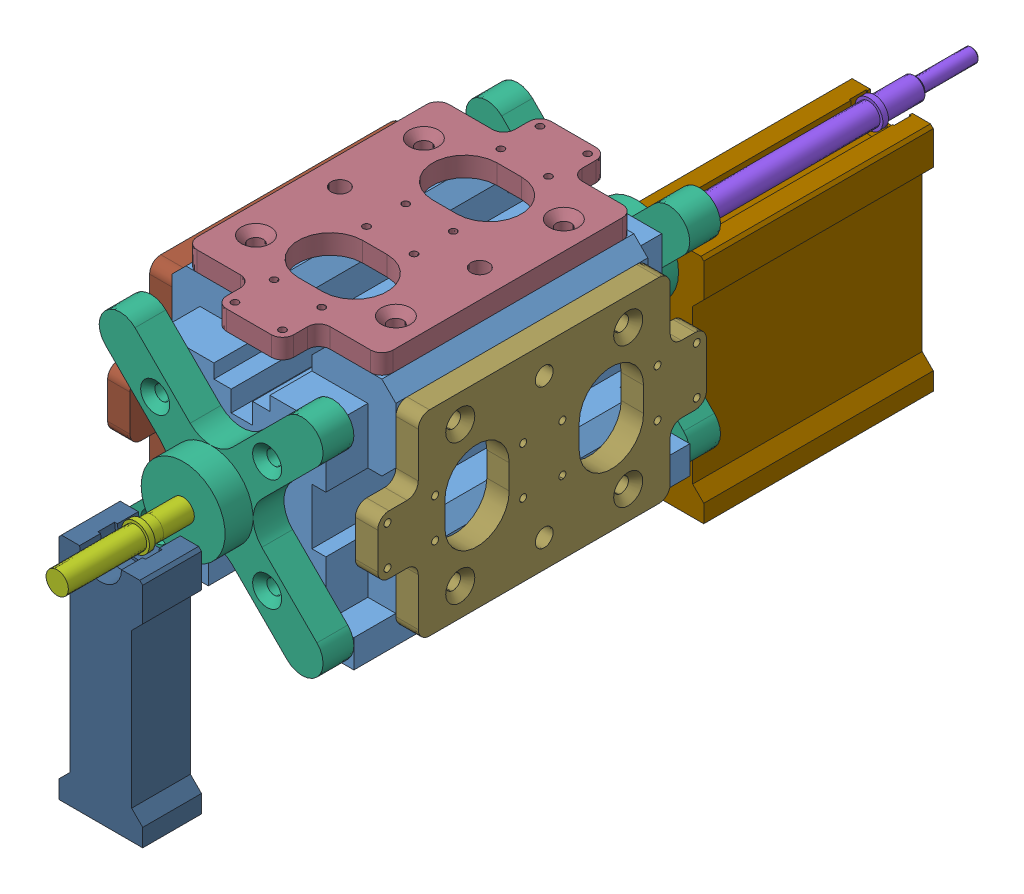
SolidWorks assembly stand, configuration Default. Lengths in mm.
Overall size (96 129.27 327).
14 component instances, 13 part files, 33 mates.
Components (placement in the parent):
- stand_base-1: stand_base [По умолчанию] at origin size (80 80 120)
- stand_plug.backb_ad22286-1: stand_plug.backb_ad22286 [По умолчанию] at (0 -24.04 12) size (24 24 18)
- stand_plug.front_crm100-1: stand_plug.front_crm100 [По умолчанию] at (0 0 108) x (-1 0 0) z (0 0 -1) size (24 24 18)
- stand_plug.frontb_ad22286-1: stand_plug.frontb_ad22286 [По умолчанию] at (0 -24.04 108) x (-1 0 0) z (0 0 -1) size (24 24 18)
- stand_plug.back_max21000-2: stand_plug.back_max21000 [По умолчанию] at (0 0 12) size (24 24 18)
- stand_cover-1: stand_cover [По умолчанию] x (-1 0 0) z (0 0 -1) size (80 80 23)
- stand_cover-2: stand_cover [По умолчанию] at (0 0 120) size (80 80 23)
- front_axis-1: front_axis [Spur01] at (0 0 141) size (10 10 74)
- axis-1: axis [Spur01] at (0 0 -21) x (-0.923728 -0.383049 0) z (0 0 -1) size (10 10 148)
- back_axis_support-1: back_axis_support [Default] at (0 0 -30) size (30 82.27 82)
- front_axis_support-1: front_axis_support [По умолчанию] at (0 0 149.5) size (30 82.27 21)
- stand_rail.left_crm100.adxl001.adxl001-2: stand_rail.left_crm100.adxl001.adxl001 [По умолчанию] at (-48 0 0) x (0 0 1) z (0 -1 0) size (118 8 70)
- stand_rail.right_ad22284.ad22283.ad22282-2: stand_rail.right_ad22284.ad22283.ad22282 [По умолчанию] at (48 0 120) x (0 0 -1) z (0 -1 0) size (117.45 8 70)
- stand_rail.top_crm100.ad22283.ad22282-2: stand_rail.top_crm100.ad22283.ad22282 [По умолчанию] at (0 47 120) x (0 0 -1) z (1 0 0) size (115.98 7 70)
Mates (geometry in assembly coordinates):
- Lock33: lock: unknown of stand_base-1; unknown of stand_plug.backb_ad22286-1
- Lock35: lock: unknown of stand_base-1; unknown of stand_plug.frontb_ad22286-1
- Lock36: lock: unknown of stand_base-1; unknown of stand_plug.front_crm100-1
- Концентричный3: concentric aligned: cylinder of stand_base-1 through (6 -24.04 22) axis (0 0 -1) radius 1.25; cylinder of stand_plug.backb_ad22286-1 through (6 -24.04 12) axis (0 0 -1) radius 1.6
- Концентричный4: concentric aligned: cylinder of stand_base-1 through (-6 -24.04 22) axis (0 0 -1) radius 1.25; cylinder of stand_plug.backb_ad22286-1 through (-6 -24.04 12) axis (0 0 -1) radius 1.6
- Совпадение8: coincident anti-aligned: plane of stand_base-1 through (0 0 22) normal (0 0 -1); plane of stand_plug.backb_ad22286-1 through (0 -24.04 22) normal (0 0 1)
- Концентричный5: concentric aligned: cylinder of stand_base-1 through (6 0 98) axis (0 0 1) radius 1.25; cylinder of stand_plug.front_crm100-1 through (6 0 108) axis (0 0 1) radius 1.6
- Концентричный6: concentric aligned: cylinder of stand_base-1 through (-6 0 98) axis (0 0 1) radius 1.25; cylinder of stand_plug.front_crm100-1 through (-6 0 108) axis (0 0 1) radius 1.6
- Совпадение9: coincident anti-aligned: plane of stand_base-1 through (0 0 98) normal (0 0 1); plane of stand_plug.front_crm100-1 through (0 0 98) normal (0 0 -1)
- Концентричный7: concentric aligned: cylinder of stand_base-1 through (6 -24.04 98) axis (0 0 1) radius 1.25; cylinder of stand_plug.frontb_ad22286-1 through (6 -24.04 108) axis (0 0 1) radius 1.6
- Концентричный8: concentric aligned: cylinder of stand_base-1 through (-6 -24.04 98) axis (0 0 1) radius 1.25; cylinder of stand_plug.frontb_ad22286-1 through (-6 -24.04 108) axis (0 0 1) radius 1.6
- Совпадение10: coincident anti-aligned: plane of stand_base-1 through (0 0 98) normal (0 0 1); plane of stand_plug.frontb_ad22286-1 through (0 -24.04 98) normal (0 0 -1)
- Концентричный9: concentric aligned: cylinder of stand_base-1 through (6 0 22) axis (0 0 -1) radius 1.25; cylinder of stand_plug.back_max21000-2 through (6 0 12) axis (0 0 -1) radius 1.6
- Концентричный10: concentric aligned: cylinder of stand_base-1 through (-6 0 22) axis (0 0 -1) radius 1.25; cylinder of stand_plug.back_max21000-2 through (-6 0 12) axis (0 0 -1) radius 1.6
- Совпадение13: coincident anti-aligned: plane of stand_base-1 through (0 0 22) normal (0 0 -1); plane of stand_plug.back_max21000-2 through (0 0 22) normal (0 0 1)
- Концентричный11: concentric aligned: cylinder of stand_base-1 through (-20 20 0) axis (0 0 -1) radius 2.1; cylinder of stand_cover-1 through (-20 20 -11) axis (0 0 -1) radius 2.65
- Концентричный12: concentric aligned: cylinder of stand_base-1 through (20 -20 0) axis (0 0 -1) radius 2.1; cylinder of stand_cover-1 through (20 -20 -11) axis (0 0 -1) radius 2.65
- Совпадение14: coincident anti-aligned: plane of stand_base-1 through (0 0 0) normal (0 0 -1); plane of stand_cover-1 through (32.5 32.5 0) normal (0 0 1)
- Концентричный13: concentric aligned: cylinder of stand_base-1 through (20 20 120) axis (0 0 1) radius 2.1; cylinder of stand_cover-2 through (20 20 131) axis (0 0 1) radius 2.65
- Концентричный14: concentric aligned: cylinder of stand_base-1 through (-20 -20 120) axis (0 0 1) radius 2.1; cylinder of stand_cover-2 through (-20 -20 131) axis (0 0 1) radius 2.65
- Совпадение15: coincident anti-aligned: plane of stand_base-1 through (0 0 120) normal (0 0 1); plane of stand_cover-2 through (-32.5 32.5 120) normal (0 0 -1)
- Совпадение16: coincident aligned: circle of stand_cover-2; circle of front_axis-1
- Совпадение18: coincident aligned: circle of stand_cover-1; circle of axis-1
- Концентричный16: concentric anti-aligned: cylinder of axis-1 through (0 0 -106) axis (0 0 -1) radius 4; cylinder of back_axis_support-1 through (0 0 -112) axis (0 0 1) radius 7.5
- Расстояние1: distance = 1 mm anti-aligned: plane of axis-1 through (-7.5377 -3.1257 -38) normal (0 0 -1); plane of back_axis_support-1 through (7.5 0 -37) normal (0 0 1)
- Концентричный17: concentric anti-aligned: cylinder of front_axis-1 through (0 0 186) axis (0 0 1) radius 4; cylinder of front_axis_support-1 through (0 0 149.5) axis (0 0 -1) radius 8.5
- Расстояние2: distance = 1 mm aligned: plane of front_axis-1 through (8.1601 0 158) normal (0 0 1); plane of front_axis_support-1 through (-8.5 0 157) normal (0 0 1)
- Совпадение23: coincident: cone of stand_base-1 through (-25 40 60) axis (0 -1 0); cone of stand_rail.top_crm100.ad22283.ad22282-2 through (-25 40 60) axis (0 -1 0)
- Совпадение24: coincident: cone of stand_base-1 through (25 40 60) axis (0 -1 0); cone of stand_rail.top_crm100.ad22283.ad22282-2 through (25 40 60) axis (0 -1 0)
- Совпадение25: coincident: cone of stand_base-1 through (-40 25 60) axis (1 0 0); cone of stand_rail.left_crm100.adxl001.adxl001-2 through (-40 25 60) axis (1 0 0)
- Совпадение26: coincident: cone of stand_base-1 through (-40 -25 60) axis (1 0 0); cone of stand_rail.left_crm100.adxl001.adxl001-2 through (-40 -25 60) axis (1 0 0)
- Совпадение27: coincident: cone of stand_base-1 through (40 25 60) axis (-1 0 0); cone of stand_rail.right_ad22284.ad22283.ad22282-2 through (40 25 60) axis (-1 0 0)
- Совпадение28: coincident: cone of stand_base-1 through (40 -25 60) axis (-1 0 0); cone of stand_rail.right_ad22284.ad22283.ad22282-2 through (40 -25 60) axis (-1 0 0)
